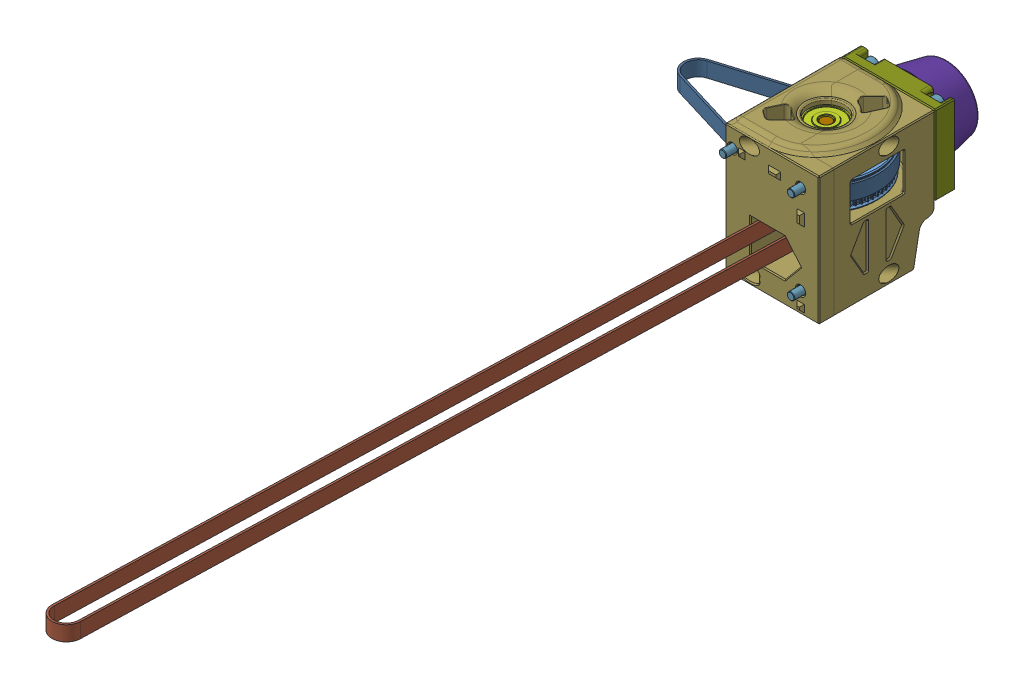
SolidWorks assembly Z-New Z Drive, configuration Z-split. Lengths in mm.
Overall size (109.5 127.78 351.64).
67 component instances, 35 part files, 49 mates.
Components (placement in the parent):
- Shaft Assembly  (1) (1) (2)^Z-New Z Drive-1: Shaft Assembly  (1) (1) (2)^Z-New Z Drive [Default] at (95.7513 0.1335 -348.8868) x (-0.819152 0 0.573576) z (-0.573576 0 -0.819152) size (88.47 47.67 79.49) (virtual, flexible)
  - 64T Front Pulley Gear (1) (2) (2) (1) (1) (1) (1) (1) (1) (2)^Shaft Assembly  (1) (1) (2)_Z-New Z Drive-1: 64T Front Pulley Gear (1) (2) (2) (1) (1) (1) (1) (1) (1) (2)^Shaft Assembly  (1) (1) (2)_Z-New Z Drive [Default] at (103.5087 103.3007 -157.3559) x (0.815878 0 0.578224) z (0 1 0) size (53.63 53.63 16) (virtual)
    - 64T Front Pulley Gear (3) (2) (1) (1) (1) (1) (1) (1) (2)^64T Front Pulley Gear (1) (2) (2) (1) (1) (1) (1) (1) (1) (2)_Shaft Assembly  (1) (1) (2)_Z-New Z Drive-1: 64T Front Pulley Gear (3) (2) (1) (1) (1) (1) (1) (1) (2)^64T Front Pulley Gear (1) (2) (2) (1) (1) (1) (1) (1) (1) (2)_Shaft Assembly  (1) (1) (2)_Z-New Z Drive [Default] at (-3.0415 1.9635 -1.417) x (0.383262 0.92364 0) z (0 0 1) size (41.03 41.03 11.2) (virtual)
    - GT2 16T 6mm - Deflanged (4) (2) (1) (1) (1) (1) (1) (1) (2)^64T Front Pulley Gear (1) (2) (2) (1) (1) (1) (1) (1) (1) (2)_Shaft Assembly  (1) (1) (2)_Z-New Z Drive-1: GT2 16T 6mm - Deflanged (4) (2) (1) (1) (1) (1) (1) (1) (2)^64T Front Pulley Gear (1) (2) (2) (1) (1) (1) (1) (1) (1) (2)_Shaft Assembly  (1) (1) (2)_Z-New Z Drive [Default] at (-3.4656 2.1394 -3.0177) x (0 0 1) z (-0.383262 -0.92364 0) size (3 2.5 3) (virtual)
    - GT2 16T 6mm - Deflanged (1) (2) (2) (1) (1) (1) (1) (1) (1) (2)^64T Front Pulley Gear (1) (2) (2) (1) (1) (1) (1) (1) (1) (2)_Shaft Assembly  (1) (1) (2)_Z-New Z Drive-1: GT2 16T 6mm - Deflanged (1) (2) (2) (1) (1) (1) (1) (1) (1) (2)^64T Front Pulley Gear (1) (2) (2) (1) (1) (1) (1) (1) (1) (2)_Shaft Assembly  (1) (1) (2)_Z-New Z Drive [Default] at (-3.2175 1.5395 -3.0177) x (0 0 1) z (-0.383262 -0.92364 0) size (3 3 2.5) (virtual)
    - GT2 16T 6mm - Deflanged (2) (2) (2) (1) (1) (1) (1) (1) (1) (2)^64T Front Pulley Gear (1) (2) (2) (1) (1) (1) (1) (1) (1) (2)_Shaft Assembly  (1) (1) (2)_Z-New Z Drive-1: GT2 16T 6mm - Deflanged (2) (2) (2) (1) (1) (1) (1) (1) (1) (2)^64T Front Pulley Gear (1) (2) (2) (1) (1) (1) (1) (1) (1) (2)_Shaft Assembly  (1) (1) (2)_Z-New Z Drive [Default] at (-3.0415 1.9635 -3.0177) x (0 0 1) z (-0.383262 -0.92364 0) size (16 13.9 13.9) (virtual)
    - socket set screw cup point_am(B18.3.6M - M3 x 0.5 x 6 Hex Socket Type I Cup Pt (2) (2) (1) (1) (1) (1) (1) (1) (2)^64T Front Pulley Gear (1) (2) (2) (1) (1) (1) (1) (1) (1) (2)_Shaft Assembly ~-7: socket set screw cup point_am(B18.3.6M - M3 x 0.5 x 6 Hex Socket Type I Cup Pt (2) (2) (1) (1) (1) (1) (1) (1) (2)^64T Front Pulley Gear (1) (2) (2) (1) (1) (1) (1) (1) (1) (2)_Shaft Assembly ~ [Default] at (2.3039 -0.2546 11.4323) x (0 0 -1) z (0.383262 0.92364 0) size (6 14.57 14.57) (virtual)
  - M5x.5mm Washer (1) (1) (1) (1) (1) (1) (2)^Shaft Assembly  (1) (1) (2)_Z-New Z Drive-1: M5x.5mm Washer (1) (1) (1) (1) (1) (1) (2)^Shaft Assembly  (1) (1) (2)_Z-New Z Drive [Default] at (102.1625 85.1157 -160.7166) x (0.367296 0 -0.930104) z (0 -1 0) size (10 10 0.5) (virtual)
  - 625 2RS (1) (2) (2) (1) (1) (1) (1) (1) (1) (2)^Shaft Assembly  (1) (1) (2)_Z-New Z Drive-1: 625 2RS (1) (2) (2) (1) (1) (1) (1) (1) (1) (2)^Shaft Assembly  (1) (1) (2)_Z-New Z Drive [Default] at (102.1625 125.183 -160.7166) x (0.367296 0 -0.930104) z (-0.930104 0 -0.367296) size (16 5 16) (virtual)
  - 625 2RS (1) (2) (2) (1) (1) (1) (1) (1) (1) (2)^Shaft Assembly  (1) (1) (2)_Z-New Z Drive-2: 625 2RS (1) (2) (2) (1) (1) (1) (1) (1) (1) (2)^Shaft Assembly  (1) (1) (2)_Z-New Z Drive [Default] at (102.1625 83.183 -160.7166) x (0.367296 0 -0.930104) z (-0.930104 0 -0.367296) size (16 5 16) (virtual)
  - GT2 16T v2 (1) (1)(Mirror) (1) (2) (2) (1) (1) (1) (1) (1) (1) (2)^Shaft Assembly  (1) (1) (2)_Z-New Z Drive-1: GT2 16T v2 (1) (1)(Mirror) (1) (2) (2) (1) (1) (1) (1) (1) (1) (2)^Shaft Assembly  (1) (1) (2)_Z-New Z Drive [Default] at (102.1625 81.783 -160.7166) x (0 1 0) z (0.755903 0 -0.654684) size (15.5 13.9 13.9) (virtual)
  - 5mm shaft (2) (2) (1) (1) (1) (1) (1) (1) (2)^Shaft Assembly  (1) (1) (2)_Z-New Z Drive-1: 5mm shaft (2) (2) (1) (1) (1) (1) (1) (1) (2)^Shaft Assembly  (1) (1) (2)_Z-New Z Drive [Default] at (102.0621 54.7827 -155.0751) x (0 1 0) z (0.367296 0 -0.930104) size (47 5 5) (virtual)
  - M5x.5mm Washer (1) (1) (1) (1) (1) (1) (2)^Shaft Assembly  (1) (1) (2)_Z-New Z Drive-2: M5x.5mm Washer (1) (1) (1) (1) (1) (1) (2)^Shaft Assembly  (1) (1) (2)_Z-New Z Drive [Default] at (102.1625 84.6157 -160.7166) x (0.367296 0 -0.930104) z (0 -1 0) size (10 10 0.5) (virtual)
  - M5x.5mm Washer (1) (1) (1) (1) (1) (1) (2)^Shaft Assembly  (1) (1) (2)_Z-New Z Drive-3: M5x.5mm Washer (1) (1) (1) (1) (1) (1) (2)^Shaft Assembly  (1) (1) (2)_Z-New Z Drive [Default] at (102.1625 84.1157 -160.7166) x (0.367296 0 -0.930104) z (0 -1 0) size (10 10 0.5) (virtual)
  - GT2-188 Belt Loop (2) (1) (1) (1) (1) (1) (1) (2)^Shaft Assembly  (1) (1) (2)_Z-New Z Drive-1: GT2-188 Belt Loop (2) (1) (1) (1) (1) (1) (1) (2)^Shaft Assembly  (1) (1) (2)_Z-New Z Drive [Default] at (278.7185 0 -230.7514) x (-0.819152 0 -0.573576) z (0.573576 0 -0.819152) size (78.6 6 42) (virtual)
- Z Idler (1) (1) (2)^Z-New Z Drive-1: Z Idler (1) (1) (2)^Z-New Z Drive [Default] at (81.8152 70.5622 -204.6072) x (0 1 0) z (0 0 -1) size (37.74 26.65 33.88) (hidden, virtual)
  - Z Idler Hardware (2) (2) (1) (1) (1) (1) (1) (1) (2)^Z Idler (1) (1) (2)_Z-New Z Drive-1: Z Idler Hardware (2) (2) (1) (1) (1) (1) (1) (1) (2)^Z Idler (1) (1) (2)_Z-New Z Drive [Default] at origin size (21.65 26.65 31.38) (virtual)
    - f623_stack (2) (2) (1) (1) (1) (1) (1) (1) (2)^Z Idler Hardware (2) (2) (1) (1) (1) (1) (1) (1) (2)_Z Idler (1) (1) (2)_Z-New Z Drive-1: f623_stack (2) (2) (1) (1) (1) (1) (1) (1) (2)^Z Idler Hardware (2) (2) (1) (1) (1) (1) (1) (1) (2)_Z Idler (1) (1) (2)_Z-New Z Drive [Default] at (41.1064 9.5714 -382.996) x (0 0 -1) z (1 0 0) size (15.29 15.29 8) (virtual)
      - f623-rs (1)(Mirror)(Mirror) (1)(Mirror) (2) (2) (1) (1) (1) (1) (1) (1) (2)^f623_stack (2) (2) (1) (1) (1) (1) (1) (1) (2)_Z Idler Hardware (2) (2) (1) (1) (1) (1) (1) (1) (2)_Z Idler (1) (1) ~-1: f623-rs (1)(Mirror)(Mirror) (1)(Mirror) (2) (2) (1) (1) (1) (1) (1) (1) (2)^f623_stack (2) (2) (1) (1) (1) (1) (1) (1) (2)_Z Idler Hardware (2) (2) (1) (1) (1) (1) (1) (1) (2)_Z Idler (1) (1) ~ [Default] at (-39.1834 4.0141 -21.5494) x (0.923728 0.383049 0) z (0 0 -1) size (11.7 11.7 4) (virtual)
      - f623-rs (1)(Mirror)(Mirror) (1)(Mirror) (2) (2) (1) (1) (1) (1) (1) (1) (2)^f623_stack (2) (2) (1) (1) (1) (1) (1) (1) (2)_Z Idler Hardware (2) (2) (1) (1) (1) (1) (1) (1) (2)_Z Idler (1) (1) ~-2: f623-rs (1)(Mirror)(Mirror) (1)(Mirror) (2) (2) (1) (1) (1) (1) (1) (1) (2)^f623_stack (2) (2) (1) (1) (1) (1) (1) (1) (2)_Z Idler Hardware (2) (2) (1) (1) (1) (1) (1) (1) (2)_Z Idler (1) (1) ~ [Default] at (-39.1834 4.0141 -17.9494) size (11.7 11.7 4) (virtual)
    - M3x25 BHCS (2) (2) (1) (1) (1) (1) (1) (1) (2)^Z Idler Hardware (2) (2) (1) (1) (1) (1) (1) (1) (2)_Z Idler (1) (1) (2)_Z-New Z Drive-1: M3x25 BHCS (2) (2) (1) (1) (1) (1) (1) (1) (2)^Z Idler Hardware (2) (2) (1) (1) (1) (1) (1) (1) (2)_Z Idler (1) (1) (2)_Z-New Z Drive [Default] at (38.0515 -176.8064 -348.5) x (0 1 0) z (-1 0 0) size (26.65 5.7 5.7) (virtual)
    - M3x25 BHCS (2) (2) (1) (1) (1) (1) (1) (1) (2)^Z Idler Hardware (2) (2) (1) (1) (1) (1) (1) (1) (2)_Z Idler (1) (1) (2)_Z-New Z Drive-2: M3x25 BHCS (2) (2) (1) (1) (1) (1) (1) (1) (2)^Z Idler Hardware (2) (2) (1) (1) (1) (1) (1) (1) (2)_Z Idler (1) (1) (2)_Z-New Z Drive [Default] at (50.5295 -176.8064 -348.5) x (0 1 0) z (-1 0 0) size (26.65 5.7 5.7) (virtual)
    - M3x12 SHCS(Mirror) (2) (2) (1) (1) (1) (1) (1) (1) (2)^Z Idler Hardware (2) (2) (1) (1) (1) (1) (1) (1) (2)_Z Idler (1) (1) (2)_Z-New Z Drive-1: M3x12 SHCS(Mirror) (2) (2) (1) (1) (1) (1) (1) (1) (2)^Z Idler Hardware (2) (2) (1) (1) (1) (1) (1) (1) (2)_Z Idler (1) (1) (2)_Z-New Z Drive [Default] at (21.5568 9.4 -350.5435) x (0 0 -1) z (-1 0 0) size (15 5.5 5.5) (virtual)
    - M3_Hex_Nut (1) (2) (2) (1) (1) (1) (1) (1) (1) (2)^Z Idler Hardware (2) (2) (1) (1) (1) (1) (1) (1) (2)_Z Idler (1) (1) (2)_Z-New Z Drive-1: M3_Hex_Nut (1) (2) (2) (1) (1) (1) (1) (1) (1) (2)^Z Idler Hardware (2) (2) (1) (1) (1) (1) (1) (1) (2)_Z Idler (1) (1) (2)_Z-New Z Drive [Default] at origin size (6.58 5.71 2.5) (virtual)
    - M3x25 BHCS  (1)(Mirror) (2) (2) (1) (1) (1) (1) (1) (1) (2)^Z Idler Hardware (2) (2) (1) (1) (1) (1) (1) (1) (2)_Z Idler (1) (1) (2)_Z-New Z Drive-1: M3x25 BHCS  (1)(Mirror) (2) (2) (1) (1) (1) (1) (1) (1) (2)^Z Idler Hardware (2) (2) (1) (1) (1) (1) (1) (1) (2)_Z Idler (1) (1) (2)_Z-New Z Drive [Default] at (-166.1216 -0.5 -366.7934) size (21.65 5.7 5.7) (virtual)
    - M3_Hex_Nut (3) (2) (1) (1) (1) (1) (1) (1) (2)^Z Idler Hardware (2) (2) (1) (1) (1) (1) (1) (1) (2)_Z Idler (1) (1) (2)_Z-New Z Drive-1: M3_Hex_Nut (3) (2) (1) (1) (1) (1) (1) (1) (2)^Z Idler Hardware (2) (2) (1) (1) (1) (1) (1) (1) (2)_Z Idler (1) (1) (2)_Z-New Z Drive [Default] at (27.6598 21.3512 -362.55) x (-1 0 0) z (0 0 1) size (5.5 2.4 6.35) (virtual)
    - M3_Hex_Nut (3) (2) (1) (1) (1) (1) (1) (1) (2)^Z Idler Hardware (2) (2) (1) (1) (1) (1) (1) (1) (2)_Z Idler (1) (1) (2)_Z-New Z Drive-2: M3_Hex_Nut (3) (2) (1) (1) (1) (1) (1) (1) (2)^Z Idler Hardware (2) (2) (1) (1) (1) (1) (1) (1) (2)_Z Idler (1) (1) (2)_Z-New Z Drive [Default] at (15.1818 21.3512 -362.55) x (-1 0 0) z (0 0 1) size (5.5 2.4 6.35) (virtual)
    - m3x.5 spacer (2) (1) (1) (1) (1) (1) (1) (2)^Z Idler Hardware (2) (2) (1) (1) (1) (1) (1) (1) (2)_Z Idler (1) (1) (2)_Z-New Z Drive-1: m3x.5 spacer (2) (1) (1) (1) (1) (1) (1) (2)^Z Idler Hardware (2) (2) (1) (1) (1) (1) (1) (1) (2)_Z Idler (1) (1) (2)_Z-New Z Drive [Default] at (-70.5622 -90.9488 -205) x (0 -1 0) z (0 0 -1) size (7 0.5 7) (virtual)
    - m3x.5 spacer (2) (1) (1) (1) (1) (1) (1) (2)^Z Idler Hardware (2) (2) (1) (1) (1) (1) (1) (1) (2)_Z Idler (1) (1) (2)_Z-New Z Drive-2: m3x.5 spacer (2) (1) (1) (1) (1) (1) (1) (2)^Z Idler Hardware (2) (2) (1) (1) (1) (1) (1) (1) (2)_Z Idler (1) (1) (2)_Z-New Z Drive [Default] at (-79.0622 -90.9488 -205) x (0 -1 0) z (0 0 -1) size (7 0.5 7) (virtual)
  - Z Tensioner (2) (2) (1) (1) (1) (1) (1) (1) (2)^Z Idler (1) (1) (2)_Z-New Z Drive-1: Z Tensioner (2) (2) (1) (1) (1) (1) (1) (1) (2)^Z Idler (1) (1) (2)_Z-New Z Drive [Default] at (-4.8272 -36.0072 -7.524) size (20.5 13.43 27.03) (virtual)
  - Z Idler (1) (1) (2)-43^Z Idler (1) (1) (2)_Z-New Z Drive-1: Z Idler (1) (1) (2)-43^Z Idler (1) (1) (2)_Z-New Z Drive [Default] at origin size (37.74 19.4 15) (virtual)
- Z Motor (1) (1) (2)^Z-New Z Drive-1: Z Motor (1) (1) (2)^Z-New Z Drive [Default] at (-4.232 0 0) size (38.47 73.89 46.71) (hidden, virtual)
  - NEMA14 Stepper  (2) (2) (1) (1) (1) (1) (1) (1) (2)^Z Motor (1) (1) (2)_Z-New Z Drive-1: NEMA14 Stepper  (2) (2) (1) (1) (1) (1) (1) (1) (2)^Z Motor (1) (1) (2)_Z-New Z Drive [Default] at (74.4075 59.0804 -141.0739) x (0 0 1) z (-1 0 0) size (38.47 73.89 38.47) (virtual)
    - GT2 16T (2) (2) (1) (1) (1) (1) (1) (1) (2)^NEMA14 Stepper  (2) (2) (1) (1) (1) (1) (1) (1) (2)_Z Motor (1) (1) (2)_Z-New Z Drive-1: GT2 16T (2) (2) (1) (1) (1) (1) (1) (1) (2)^NEMA14 Stepper  (2) (2) (1) (1) (1) (1) (1) (1) (2)_Z Motor (1) (1) (2)_Z-New Z Drive [Default] at (-96.0075 -200.8988 -75.6556) x (0.343907 -0.939004 0) z (0 0 -1) size (19.21 18.26 13.9) (virtual)
    - NEMA14 Stepper  (2) (2) (1) (1) (1) (1) (1) (1) (2)-44^NEMA14 Stepper  (2) (2) (1) (1) (1) (1) (1) (1) (2)_Z Motor (1) (1) (2)_Z-New Z Drive-1: NEMA14 Stepper  (2) (2) (1) (1) (1) (1) (1) (1) (2)-44^NEMA14 Stepper  (2) (2) (1) (1) (1) (1) (1) (1) (2)_Z Motor (1) (1) (2)_Z-New Z Drive [Default] at origin size (38.47 73.29 38.47) (virtual)
  - Hardware (2) (2) (1) (1) (1) (1) (1) (1) (2)^Z Motor (1) (1) (2)_Z-New Z Drive-1: Hardware (2) (2) (1) (1) (1) (1) (1) (1) (2)^Z Motor (1) (1) (2)_Z-New Z Drive [Default] at (-1.75 0 0) size (31.39 22.35 44.61) (virtual)
    - M3x12 SHCS v1 (2) (2) (1) (1) (1) (1) (3) (1) (2)^Hardware (2) (2) (1) (1) (1) (1) (1) (1) (2)_Z Motor (1) (1) (2)_Z-New Z Drive-1: M3x12 SHCS v1 (2) (2) (1) (1) (1) (1) (3) (1) (2)^Hardware (2) (2) (1) (1) (1) (1) (1) (1) (2)_Z Motor (1) (1) (2)_Z-New Z Drive [Default] at (45.7271 67.583 -171.9687) x (-1 0 0) z (0 -1 0) size (5.5 5.5 15) (virtual)
    - M3_Hex_Nut v1 (5) (2) (1) (1) (1) (1) (1) (1) (1) (2)^Hardware (2) (2) (1) (1) (1) (1) (1) (1) (2)_Z Motor (1) (1) (2)_Z-New Z Drive-1: M3_Hex_Nut v1 (5) (2) (1) (1) (1) (1) (1) (1) (1) (2)^Hardware (2) (2) (1) (1) (1) (1) (1) (1) (2)_Z Motor (1) (1) (2)_Z-New Z Drive [Default] at (69.1922 117.083 -132.6999) x (0 1 0) z (1 0 0) size (5.5 2.4 6.35) (virtual)
    - M3_Hex_Nut v1 (5) (2) (1) (1) (1) (1) (1) (1) (1) (2)^Hardware (2) (2) (1) (1) (1) (1) (1) (1) (2)_Z Motor (1) (1) (2)_Z-New Z Drive-2: M3_Hex_Nut v1 (5) (2) (1) (1) (1) (1) (1) (1) (1) (2)^Hardware (2) (2) (1) (1) (1) (1) (1) (1) (2)_Z Motor (1) (1) (2)_Z-New Z Drive [Default] at (47.4922 117.083 -132.6999) x (0 1 0) z (1 0 0) size (5.5 2.4 6.35) (virtual)
    - M3x10 BHCS v2 (2) (1) (1) (1) (1) (1) (1) (2)^Hardware (2) (2) (1) (1) (1) (1) (1) (1) (2)_Z Motor (1) (1) (2)_Z-New Z Drive-1: M3x10 BHCS v2 (2) (1) (1) (1) (1) (1) (1) (2)^Hardware (2) (2) (1) (1) (1) (1) (1) (1) (2)_Z Motor (1) (1) (2)_Z-New Z Drive [Default] at (69.1922 117.083 -142.9419) x (0 -1 0) z (0 0 -1) size (5.7 5.7 11.65) (virtual)
    - M3x10 BHCS v2 (2) (1) (1) (1) (1) (1) (1) (2)^Hardware (2) (2) (1) (1) (1) (1) (1) (1) (2)_Z Motor (1) (1) (2)_Z-New Z Drive-2: M3x10 BHCS v2 (2) (1) (1) (1) (1) (1) (1) (2)^Hardware (2) (2) (1) (1) (1) (1) (1) (1) (2)_Z Motor (1) (1) (2)_Z-New Z Drive [Default] at (47.4922 117.083 -142.9419) x (0 -1 0) z (0 0 -1) size (5.7 5.7 11.65) (virtual)
    - M3x12 SHCS v1 (2) (2) (1) (1) (1) (1) (1) (1) (1) (2)^Hardware (2) (2) (1) (1) (1) (1) (1) (1) (2)_Z Motor (1) (1) (2)_Z-New Z Drive-1: M3x12 SHCS v1 (2) (2) (1) (1) (1) (1) (1) (1) (1) (2)^Hardware (2) (2) (1) (1) (1) (1) (1) (1) (2)_Z Motor (1) (1) (2)_Z-New Z Drive [Default] at (44.9681 67.583 -145.9798) x (-1 0 0) z (0 -1 0) size (5.5 5.5 15) (virtual)
    - M3x12 SHCS v1 (2) (2) (1) (1) (1) (1) (2) (1) (1) (2)^Hardware (2) (2) (1) (1) (1) (1) (1) (1) (2)_Z Motor (1) (1) (2)_Z-New Z Drive-1: M3x12 SHCS v1 (2) (2) (1) (1) (1) (1) (2) (1) (1) (2)^Hardware (2) (2) (1) (1) (1) (1) (1) (1) (2)_Z Motor (1) (1) (2)_Z-New Z Drive [Default] at (70.9573 67.583 -145.2311) x (-1 0 0) z (0 -1 0) size (5.5 5.5 15) (virtual)
- Z-Belt (1) (1) (2)^Z-New Z Drive-1: Z-Belt (1) (1) (2)^Z-New Z Drive [Default] at (-6.132 -0.2657 23.3183) x (-0.999563 0 -0.029544) z (-0.029544 0 0.999563) size (11.65 6 309.55) (virtual)
- NewZDrive^Z-New Z Drive-1: NewZDrive^Z-New Z Drive [Default] at origin size (109.5 127.78 121.7) (virtual)
- M3 Threaded Insert Short^Z-New Z Drive-1: M3 Threaded Insert Short^Z-New Z Drive [Default] at (89.1744 121.8496 -159.8274) x (0.665279 0.338832 0.665279) z (0.23959 -0.940847 0.23959) size (5.56 3.8 5.56) (virtual)
- M3 Threaded Insert Short^Z-New Z Drive-6: M3 Threaded Insert Short^Z-New Z Drive [Default] at (89.1744 77.2996 -159.8274) x (0.649438 0.39555 0.649438) z (0.279696 -0.918444 0.279696) size (5.56 3.8 5.56) (virtual)
- M3 Threaded Insert Short^Z-New Z Drive-7: M3 Threaded Insert Short^Z-New Z Drive [Default] at (119.6898 121.476 -181.8577) x (-0.999908 0.013571 0) z (-0.013571 -0.999908 0) size (5.56 3.8 5.56) (virtual)
- M3 Threaded Insert Short^Z-New Z Drive-8: M3 Threaded Insert Short^Z-New Z Drive [Default] at (93.2706 121.476 -181.8577) x (-0.989411 -0.145138 0) z (0.145138 -0.989411 0) size (5.56 3.8 5.56) (virtual)
- M3 Threaded Insert Short^Z-New Z Drive-9: M3 Threaded Insert Short^Z-New Z Drive [Default] at (93.2706 96.3627 -181.8577) x (-0.962877 -0.269941 0) z (0.269941 -0.962877 0) size (5.56 3.8 5.56) (virtual)
- M3x6 SHCS^Z-New Z Drive-1: M3x6 SHCS^Z-New Z Drive [Default] at (90 117.4996 -97.011) x (0.89523 -0.445605 0) z (0 0 -1) size (5.5 5.5 9) (virtual)
- M3x6 SHCS^Z-New Z Drive-2: M3x6 SHCS^Z-New Z Drive [Default] at (117.5 117.4996 -97.011) x (0.954557 -0.298027 0) z (0 0 -1) size (5.5 5.5 9) (virtual)
- M3x6 SHCS^Z-New Z Drive-3: M3x6 SHCS^Z-New Z Drive [Default] at (117.5 81.4996 -97.011) x (0.984736 -0.174055 0) z (0 0 -1) size (5.5 5.5 9) (virtual)
- M3x6 SHCS^Z-New Z Drive-5: M3x6 SHCS^Z-New Z Drive [Default] at (119.6898 121.476 -145.8577) x (0.470624 0.882334 0) z (0 0 -1) size (5.5 5.5 9) (virtual)
- M3x6 SHCS^Z-New Z Drive-7: M3x6 SHCS^Z-New Z Drive [Default] at (93.2706 121.476 -145.8577) x (0.999876 -0.015721 0) z (0 0 -1) size (5.5 5.5 9) (virtual)
- M3x6 SHCS^Z-New Z Drive-9: M3x6 SHCS^Z-New Z Drive [Default] at (93.2706 96.3627 -145.8577) x (-0.419713 -0.907657 0) z (0 0 -1) size (5.5 5.5 9) (virtual)
- M3 Threaded Insert Short^Z-New Z Drive-11: M3 Threaded Insert Short^Z-New Z Drive [Default] at (99.0592 121.7496 -137.1854) x (0.634686 0.440849 0.634686) z (0.311727 -0.897581 0.311727) size (5.56 3.8 5.56) (virtual)
- M3 Threaded Insert Short^Z-New Z Drive-13: M3 Threaded Insert Short^Z-New Z Drive [Default] at (99.0592 77.1996 -137.1854) x (0.631673 0.44942 0.631673) z (0.317788 -0.893321 0.317788) size (5.56 3.8 5.56) (virtual)
- M3x25 SHCS^Z-New Z Drive-1: M3x25 SHCS^Z-New Z Drive [Default] at (88.3112 121.7496 -126.4374) x (0.273403 -0.922226 0.273403) z (0.707107 0 -0.707107) size (5.5 5.5 28) (virtual)
- M3x25 SHCS^Z-New Z Drive-2: M3x25 SHCS^Z-New Z Drive [Default] at (88.3112 77.1996 -126.4374) x (0.298736 -0.906374 0.298736) z (0.707107 0 -0.707107) size (5.5 5.5 28) (virtual)
- M3x25 SHCS^Z-New Z Drive-4: M3x25 SHCS^Z-New Z Drive [Default] at (77.4541 121.8496 -148.1071) x (0.323611 -0.88913 0.323611) z (0.707107 0 -0.707107) size (5.5 5.5 28) (virtual)
- M3x25 SHCS^Z-New Z Drive-6: M3x25 SHCS^Z-New Z Drive [Default] at (77.4541 77.2996 -148.1071) x (0.347989 -0.870521 0.347989) z (0.707107 0 -0.707107) size (5.5 5.5 28) (virtual)
- ZDriveFootPlate^Z-New Z Drive-1: ZDriveFootPlate^Z-New Z Drive [Default] at (1.792 -1.417 0) size (38.29 31.99 8.04) (virtual)
- MISUMI C-30-RK-3215 Foot v1 (2) (1)^Z-New Z Drive-1: MISUMI C-30-RK-3215 Foot v1 (2) (1)^Z-New Z Drive [Default] at (6741.7678 -8809.5749 -189.8577) x (0 -1 0) z (0 0 -1) size (32 32 15.01) (virtual)
- M5x16 BHCS^Z-New Z Drive-1: M5x16 BHCS^Z-New Z Drive [Default] at (106.7519 109.0295 -155.6077) x (0 0 1) z (0 -1 0) size (18.75 9.5 9.5) (virtual)
- Copy of Z Drive Hardware (2) (1)-43^Z-New Z Drive-1: Copy of Z Drive Hardware (2) (1)-43^Z-New Z Drive [Default] at (1.792 -1.417 0) size (10.39 9 4) (virtual)
- M3 Threaded Insert Short^Z-New Z Drive-14: M3 Threaded Insert Short^Z-New Z Drive [Default] at (87 79.5496 -166.7652) x (0 0.144467 0.98951) z (0 -0.98951 0.144467) size (5.56 3.8 5.56) (virtual)
Mates (geometry in assembly coordinates):
- Coincident1: coincident anti-aligned: plane of NewZDrive^Z-New Z Drive-1 through (91.8614 121.8496 -162.5144) normal (-0.707107 0 0.707107); plane of M3 Threaded Insert Short^Z-New Z Drive-1 through (91.8614 121.8496 -162.5144) normal (0.707107 0 -0.707107)
- Concentric1: concentric aligned: cylinder of NewZDrive^Z-New Z Drive-1 through (75.6425 121.8496 -146.2956) axis (0.707107 0 -0.707107) radius 2.35; cylinder of M3 Threaded Insert Short^Z-New Z Drive-1 through (91.8614 121.8496 -162.5144) axis (0.707107 0 -0.707107) radius 1.5
- Coincident4: coincident anti-aligned: plane of NewZDrive^Z-New Z Drive-1 through (91.8614 77.2996 -162.5144) normal (-0.707107 0 0.707107); plane of M3 Threaded Insert Short^Z-New Z Drive-6 through (91.8614 77.2996 -162.5144) normal (0.707107 0 -0.707107)
- Concentric4: concentric aligned: cylinder of NewZDrive^Z-New Z Drive-1 through (75.6425 77.2996 -146.2956) axis (0.707107 0 -0.707107) radius 2.35; cylinder of M3 Threaded Insert Short^Z-New Z Drive-6 through (91.8614 77.2996 -162.5144) axis (0.707107 0 -0.707107) radius 1.5
- Coincident5: coincident aligned: plane of NewZDrive^Z-New Z Drive-1 through (0 0 -181.8577) normal (0 0 -1); plane of M3 Threaded Insert Short^Z-New Z Drive-7 through (119.6898 121.476 -181.8577) normal (0 0 -1)
- Concentric5: concentric anti-aligned: cylinder of NewZDrive^Z-New Z Drive-1 through (119.6898 121.476 -177.6077) axis (0 0 -1) radius 2.35; cylinder of M3 Threaded Insert Short^Z-New Z Drive-7 through (119.6898 121.476 -178.0577) axis (0 0 1) radius 1.5
- Coincident6: coincident aligned: plane of NewZDrive^Z-New Z Drive-1 through (0 0 -181.8577) normal (0 0 -1); plane of M3 Threaded Insert Short^Z-New Z Drive-8 through (93.2706 121.476 -181.8577) normal (0 0 -1)
- Concentric6: concentric anti-aligned: cylinder of NewZDrive^Z-New Z Drive-1 through (93.2706 121.476 -177.6077) axis (0 0 -1) radius 2.35; cylinder of M3 Threaded Insert Short^Z-New Z Drive-8 through (93.2706 121.476 -178.0577) axis (0 0 1) radius 1.5
- Coincident7: coincident aligned: plane of NewZDrive^Z-New Z Drive-1 through (0 0 -181.8577) normal (0 0 -1); plane of M3 Threaded Insert Short^Z-New Z Drive-9 through (93.2706 96.3627 -181.8577) normal (0 0 -1)
- Concentric7: concentric anti-aligned: cylinder of NewZDrive^Z-New Z Drive-1 through (93.2706 96.3627 -177.6077) axis (0 0 -1) radius 2.35; cylinder of M3 Threaded Insert Short^Z-New Z Drive-9 through (93.2706 96.3627 -178.0577) axis (0 0 1) radius 1.5
- Concentric8: concentric anti-aligned: cylinder of NewZDrive^Z-New Z Drive-1 through (90 117.4996 -181.9585) axis (0 0 1) radius 1.7; cylinder of M3x6 SHCS^Z-New Z Drive-1 through (90 117.4996 -137.011) axis (0 0 -1) radius 1.5
- Coincident10: coincident anti-aligned: plane of NewZDrive^Z-New Z Drive-1 through (90 117.4996 -137.011) normal (0 0 -1); plane of M3x6 SHCS^Z-New Z Drive-1 through (90 117.4996 -137.011) normal (0 0 1)
- Concentric9: concentric anti-aligned: cylinder of NewZDrive^Z-New Z Drive-1 through (117.5 117.4996 -181.9585) axis (0 0 1) radius 1.7; cylinder of M3x6 SHCS^Z-New Z Drive-2 through (117.5 117.4996 -137.011) axis (0 0 -1) radius 1.5
- Coincident11: coincident anti-aligned: plane of NewZDrive^Z-New Z Drive-1 through (90 117.4996 -137.011) normal (0 0 -1); plane of M3x6 SHCS^Z-New Z Drive-2 through (117.5 117.4996 -137.011) normal (0 0 1)
- Coincident12: coincident anti-aligned: plane of NewZDrive^Z-New Z Drive-1 through (90 117.4996 -137.011) normal (0 0 -1); plane of M3x6 SHCS^Z-New Z Drive-3 through (117.5 81.4996 -137.011) normal (0 0 1)
- Concentric10: concentric anti-aligned: cylinder of NewZDrive^Z-New Z Drive-1 through (117.5 81.4996 -181.9585) axis (0 0 1) radius 1.7; cylinder of M3x6 SHCS^Z-New Z Drive-3 through (117.5 81.4996 -137.011) axis (0 0 -1) radius 1.5
- Coincident29: coincident anti-aligned: plane of NewZDrive^Z-New Z Drive-1 through (101.7462 121.7496 -139.8724) normal (-0.707107 0 0.707107); plane of M3 Threaded Insert Short^Z-New Z Drive-11 through (101.7462 121.7496 -139.8724) normal (0.707107 0 -0.707107)
- Concentric24: concentric anti-aligned: cylinder of NewZDrive^Z-New Z Drive-1 through (134.4163 121.7496 -172.5424) axis (-0.707107 0 0.707107) radius 1.7; cylinder of M3 Threaded Insert Short^Z-New Z Drive-11 through (101.7462 121.7496 -139.8724) axis (0.707107 0 -0.707107) radius 1.5
- Coincident30: coincident anti-aligned: plane of NewZDrive^Z-New Z Drive-1 through (101.7462 77.1996 -139.8724) normal (-0.707107 0 0.707107); plane of M3 Threaded Insert Short^Z-New Z Drive-13 through (101.7462 77.1996 -139.8724) normal (0.707107 0 -0.707107)
- Concentric25: concentric anti-aligned: cylinder of NewZDrive^Z-New Z Drive-1 through (134.4163 77.1996 -172.5424) axis (-0.707107 0 0.707107) radius 1.7; cylinder of M3 Threaded Insert Short^Z-New Z Drive-13 through (101.7462 77.1996 -139.8724) axis (0.707107 0 -0.707107) radius 1.5
- Coincident38: coincident anti-aligned: plane of NewZDrive^Z-New Z Drive-1 through (116.5955 121.7496 -154.7216) normal (0.707107 0 -0.707107); plane of M3x25 SHCS^Z-New Z Drive-1 through (116.5955 121.7496 -154.7216) normal (-0.707107 0 0.707107)
- Concentric30: concentric anti-aligned: cylinder of NewZDrive^Z-New Z Drive-1 through (134.4163 121.7496 -172.5424) axis (-0.707107 0 0.707107) radius 1.7; cylinder of M3x25 SHCS^Z-New Z Drive-1 through (116.5955 121.7496 -154.7216) axis (0.707107 0 -0.707107) radius 1.5
- Coincident39: coincident anti-aligned: plane of NewZDrive^Z-New Z Drive-1 through (116.5955 77.1996 -154.7216) normal (0.707107 0 -0.707107); plane of M3x25 SHCS^Z-New Z Drive-2 through (116.5955 77.1996 -154.7216) normal (-0.707107 0 0.707107)
- Concentric31: concentric anti-aligned: cylinder of NewZDrive^Z-New Z Drive-1 through (134.4163 77.1996 -172.5424) axis (-0.707107 0 0.707107) radius 1.7; cylinder of M3x25 SHCS^Z-New Z Drive-2 through (116.5955 77.1996 -154.7216) axis (0.707107 0 -0.707107) radius 1.5
- Coincident49: coincident anti-aligned: plane of NewZDrive^Z-New Z Drive-1 through (105.7383 121.8496 -176.3914) normal (0.707107 0 -0.707107); plane of M3x25 SHCS^Z-New Z Drive-4 through (105.7383 121.8496 -176.3914) normal (-0.707107 0 0.707107)
- Concentric41: concentric anti-aligned: cylinder of NewZDrive^Z-New Z Drive-1 through (118.1528 121.8496 -188.8059) axis (-0.707107 0 0.707107) radius 1.7; cylinder of M3x25 SHCS^Z-New Z Drive-4 through (105.7383 121.8496 -176.3914) axis (0.707107 0 -0.707107) radius 1.5
- Concentric43: concentric anti-aligned: cylinder of Shaft Assembly  (1) (1) (2)^Z-New Z Drive-1/GT2 16T v2 (1) (1)(Mirror) (1) (2) (2) (1) (1) (1) (1) (1) (1) (2)^Shaft Assembly  (1) (1) (2)_Z-New Z Drive-1 through (104.2479 81.9166 -158.6375) axis (0 -1 0) radius 4.84; cylinder of Z-Belt (1) (1) (2)^Z-New Z Drive-1 through (104.2479 88.5353 -158.6375) axis (0 1 0) radius 5.7625
- Concentric45: concentric aligned: cylinder of Z Idler (1) (1) (2)^Z-New Z Drive-1/Z Idler Hardware (2) (2) (1) (1) (1) (1) (1) (1) (2)^Z Idler (1) (1) (2)_Z-New Z Drive-1/f623_stack (2) (2) (1) (1) (1) (1) (1) (1) (2)^Z Idler Hardware (2) (2) (1) (1) (1) (1) (1) (1) (2)_Z Idler (1) (1) (2)_Z-New Z Drive-1/f623-rs (1)(Mirror)(Mirror) (1)(Mirror) (2) (2) (1) (1) (1) (1) (1) (1) (2)^f623_stack (2) (2) (1) (1) (1) (1) (1) (1) (2)_Z Idler Hardware (2) (2) (1) (1) (1) (1) (1) (1) (2)_Z Idler (1) (1) (~-1 through (95.4007 92.1191 139.2054) axis (0 -1 0) radius 5; cylinder of Z-Belt (1) (1) (2)^Z-New Z Drive-1 through (95.4007 88.9191 139.2054) axis (0 -1 0) radius 5.8173
- Coincident51: coincident anti-aligned: plane of Z Idler (1) (1) (2)^Z-New Z Drive-1/Z Idler Hardware (2) (2) (1) (1) (1) (1) (1) (1) (2)^Z Idler (1) (1) (2)_Z-New Z Drive-1/f623_stack (2) (2) (1) (1) (1) (1) (1) (1) (2)^Z Idler Hardware (2) (2) (1) (1) (1) (1) (1) (1) (2)_Z Idler (1) (1) (2)_Z-New Z Drive-1/f623-rs (1)(Mirror)(Mirror) (1)(Mirror) (2) (2) (1) (1) (1) (1) (1) (1) (2)^f623_stack (2) (2) (1) (1) (1) (1) (1) (1) (2)_Z Idler Hardware (2) (2) (1) (1) (1) (1) (1) (1) (2)_Z Idler (1) (1) (~-2 through (98.8705 94.9191 139.2054) normal (0 -1 0); plane of Z-Belt (1) (1) (2)^Z-New Z Drive-1 through (90.8921 94.9191 108.9529) normal (0 1 0)
- Concentric53: concentric aligned: cylinder of NewZDrive^Z-New Z Drive-1 through (119.6898 121.476 -174.3577) axis (0 0 -1) radius 1.7; cylinder of ZDriveFootPlate^Z-New Z Drive-1 through (119.6898 121.476 -181.8577) axis (0 0 -1) radius 1.7
- Concentric54: concentric aligned: cylinder of NewZDrive^Z-New Z Drive-1 through (93.2706 121.476 -174.3577) axis (0 0 -1) radius 1.7; cylinder of ZDriveFootPlate^Z-New Z Drive-1 through (93.2706 121.476 -181.8577) axis (0 0 -1) radius 1.7
- Coincident56: coincident anti-aligned: plane of NewZDrive^Z-New Z Drive-1 through (0 0 -181.8577) normal (0 0 -1); plane of ZDriveFootPlate^Z-New Z Drive-1 through (115.2989 109.005 -181.8577) normal (0 0 1)
- Concentric55: concentric aligned: cylinder of M3x6 SHCS^Z-New Z Drive-5 through (119.6898 121.476 -185.8577) axis (0 0 -1) radius 1.5; cylinder of ZDriveFootPlate^Z-New Z Drive-1 through (119.6898 121.476 -181.8577) axis (0 0 -1) radius 1.7
- Coincident57: coincident anti-aligned: plane of M3x6 SHCS^Z-New Z Drive-5 through (119.6898 121.476 -185.8577) normal (0 0 1); plane of ZDriveFootPlate^Z-New Z Drive-1 through (119.6898 121.7376 -185.8577) normal (0 0 -1)
- Concentric56: concentric aligned: cylinder of M3x6 SHCS^Z-New Z Drive-7 through (93.2706 121.476 -185.8577) axis (0 0 -1) radius 1.5; cylinder of ZDriveFootPlate^Z-New Z Drive-1 through (93.2706 121.476 -181.8577) axis (0 0 -1) radius 1.7
- Coincident58: coincident anti-aligned: plane of M3x6 SHCS^Z-New Z Drive-7 through (93.2706 121.476 -185.8577) normal (0 0 1); plane of ZDriveFootPlate^Z-New Z Drive-1 through (93.2706 121.476 -185.8577) normal (0 0 -1)
- Concentric57: concentric aligned: cylinder of M3x6 SHCS^Z-New Z Drive-9 through (93.2706 96.3627 -185.8577) axis (0 0 -1) radius 1.5; cylinder of ZDriveFootPlate^Z-New Z Drive-1 through (93.2706 96.3627 -181.8577) axis (0 0 -1) radius 1.7
- Coincident59: coincident anti-aligned: plane of M3x6 SHCS^Z-New Z Drive-9 through (93.2706 96.3627 -185.8577) normal (0 0 1); plane of ZDriveFootPlate^Z-New Z Drive-1 through (93.2706 96.3627 -185.8577) normal (0 0 -1)
- Concentric58: concentric anti-aligned: cylinder of NewZDrive^Z-New Z Drive-1 through (118.1528 77.2996 -188.8059) axis (-0.707107 0 0.707107) radius 1.7; cylinder of M3x25 SHCS^Z-New Z Drive-6 through (105.7383 77.2996 -176.3914) axis (0.707107 0 -0.707107) radius 1.5
- Concentric59: concentric anti-aligned: cylinder of Copy of MISUMI C-30-RK-3215 Foot v1 (2) (1)^Z-New Z Drive-1 through (106.7519 109.0295 -189.8577) axis (0 0 -1) radius 2.5; cylinder of Copy of M5x16 BHCS  (2) (1)^Z-New Z Drive-1 through (106.7519 109.0295 -202.6077) axis (0 0 1) radius 2.5
- Coincident61: coincident anti-aligned: plane of Copy of MISUMI C-30-RK-3215 Foot v1 (2) (1)^Z-New Z Drive-1 through (106.7519 109.0295 -199.8577) normal (0 0 -1); plane of Copy of M5x16 BHCS  (2) (1)^Z-New Z Drive-1 through (104.2519 109.0295 -199.8577) normal (0 0 1)
- Concentric60: concentric aligned: cylinder of ZDriveFootPlate^Z-New Z Drive-1 through (106.7519 109.0295 -185.8577) axis (0 0 1) radius 2.7; cylinder of Copy of M5x16 BHCS  (2) (1)^Z-New Z Drive-1 through (106.7519 109.0295 -202.6077) axis (0 0 1) radius 2.5
- Concentric61: concentric anti-aligned: cylinder of Copy of M5x16 BHCS  (2) (1)^Z-New Z Drive-1 through (106.7519 109.0295 -202.6077) axis (0 0 1) radius 2.5; cylinder of Copy of Z Drive Hardware (2) (1)-43^Z-New Z Drive-1 through (106.7519 109.0295 -185.8577) axis (0 0 -1) radius 2.5
- Coincident62: coincident anti-aligned: plane of ZDriveFootPlate^Z-New Z Drive-1 through (111.948 109.0295 -185.8577) normal (-0.866025 0.5 0); plane of Copy of Z Drive Hardware (2) (1)-43^Z-New Z Drive-1 through (111.948 109.0295 -185.8577) normal (0.866025 -0.5 0)
- Coincident63: coincident: line of ZDriveFootPlate^Z-New Z Drive-1 through (104.1538 113.5295 -185.8577) axis (0 -1 0); plane of Copy of Z Drive Hardware (2) (1)-43^Z-New Z Drive-1 through (107.6452 109.5264 -185.8577) normal (0 0 -1)
- Coincident64: coincident anti-aligned: plane of ZDriveFootPlate^Z-New Z Drive-1 through (115.2989 109.005 -189.8577) normal (0 0 -1); plane of Copy of MISUMI C-30-RK-3215 Foot v1 (2) (1)^Z-New Z Drive-1 through (106.7519 109.0295 -189.8577) normal (0 0 1)
- Concentric62: concentric anti-aligned: cylinder of NewZDrive^Z-New Z Drive-1 through (91 79.5496 -166.7652) axis (-1 0 0) radius 2.35; cylinder of M3 Threaded Insert Short^Z-New Z Drive-14 through (90.8 79.5496 -166.7652) axis (1 0 0) radius 1.5
- Coincident65: coincident aligned: plane of NewZDrive^Z-New Z Drive-1 through (87 73.2496 -181.8577) normal (-1 0 0); plane of M3 Threaded Insert Short^Z-New Z Drive-14 through (87 79.5496 -166.7652) normal (-1 0 0)
- Coincident69: coincident: plane of assembly; point of NewZDrive^Z-New Z Drive-1; plane of M3x25 SHCS^Z-New Z Drive-6 through (105.7383 77.2996 -176.3914) normal (-0.707107 0 0.707107)
